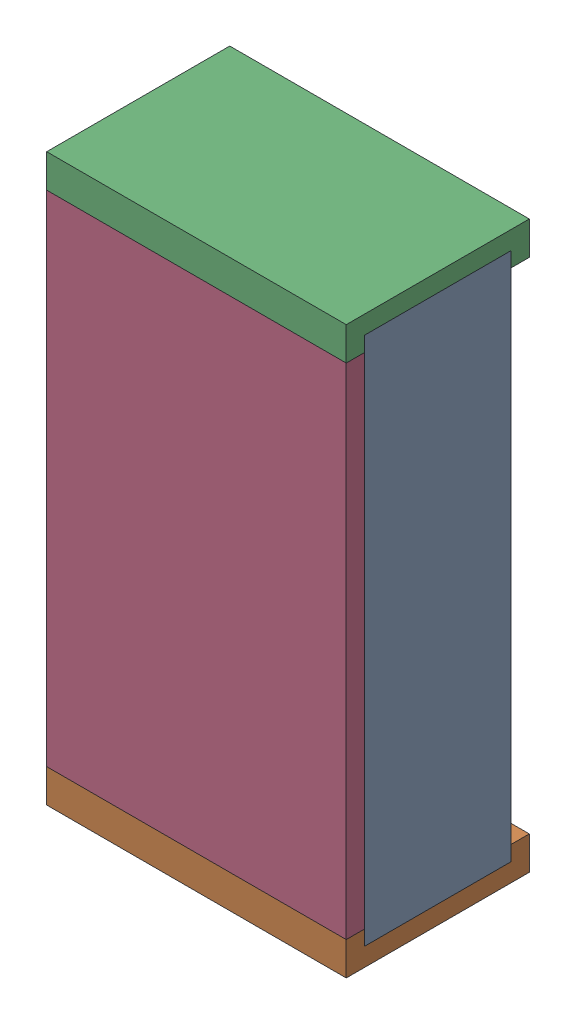
SolidWorks assembly R4, configuration Default. Lengths in mm.
Overall size (0.9 1.7 0.55).
7 component instances, 3 part files, 0 mates.
Components (placement in the parent):
- 6019289040-1: 6019289040 [Default] at (19.3039 2.6671 0) x (0 1 0) z (0 0 1) size (1.7 0.9 0.55)
  - Mid_Body-1: Mid_Body [Default] at (-0.85 -0.45 0) size (1.59 0.9 0.44)
  - Terminal-1: Terminal [Default] at (-0.85 -0.45 0) size (0.1 0.9 0.55)
    - Open CASCADE STEP translator 6.8 15.2.1-1: Open CASCADE STEP translator 6.8 15.2.1 [Default] at origin size (0.1 0.9 0.55)
  - Terminal-2: Terminal [Default] at (0.85 0.45 0) x (-1 0 0) z (0 0 1) size (0.1 0.9 0.55)
    - Open CASCADE STEP translator 6.8 15.2.1-1: Open CASCADE STEP translator 6.8 15.2.1 [Default] at origin size (0.1 0.9 0.55)
  - Mark-1: Mark [Default] at (-0.75 -0.45 0.495) size (1.5 0.9 0.06)
